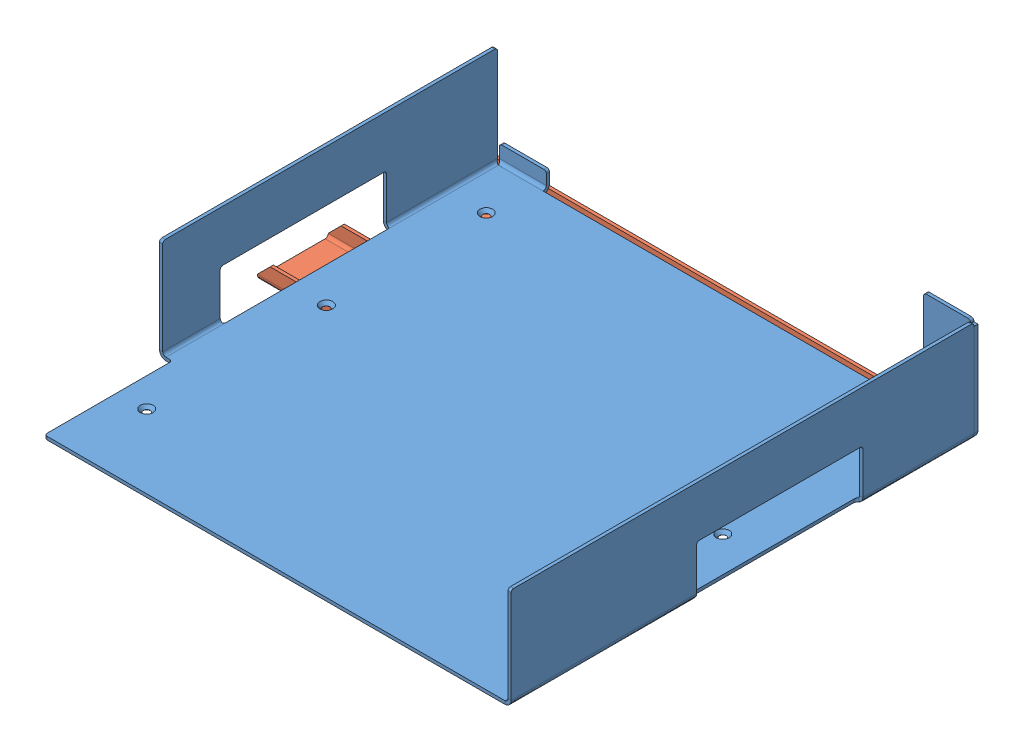
SolidWorks assembly Сборка2, configuration По умолчанию. Lengths in mm.
Overall size (505.9 197.51 454.67).
3 component instances, 2 part files, 0 mates.
Components (placement in the parent):
- 1_Полка-1: 1_Полка [По умолчанию<Как обработанный>] at (-182.6691 43.1061 558.1681) size (375.45 80.44 365.44)
- 2_Основание-1: 2_Основание [По умолчанию] at (-125.1109 -57.7699 132.4962) size (350 15 58)
- 2_Основание-2: 2_Основание [По умолчанию] at (-138.1284 -74.4024 222.1941) size (350 15 58)
